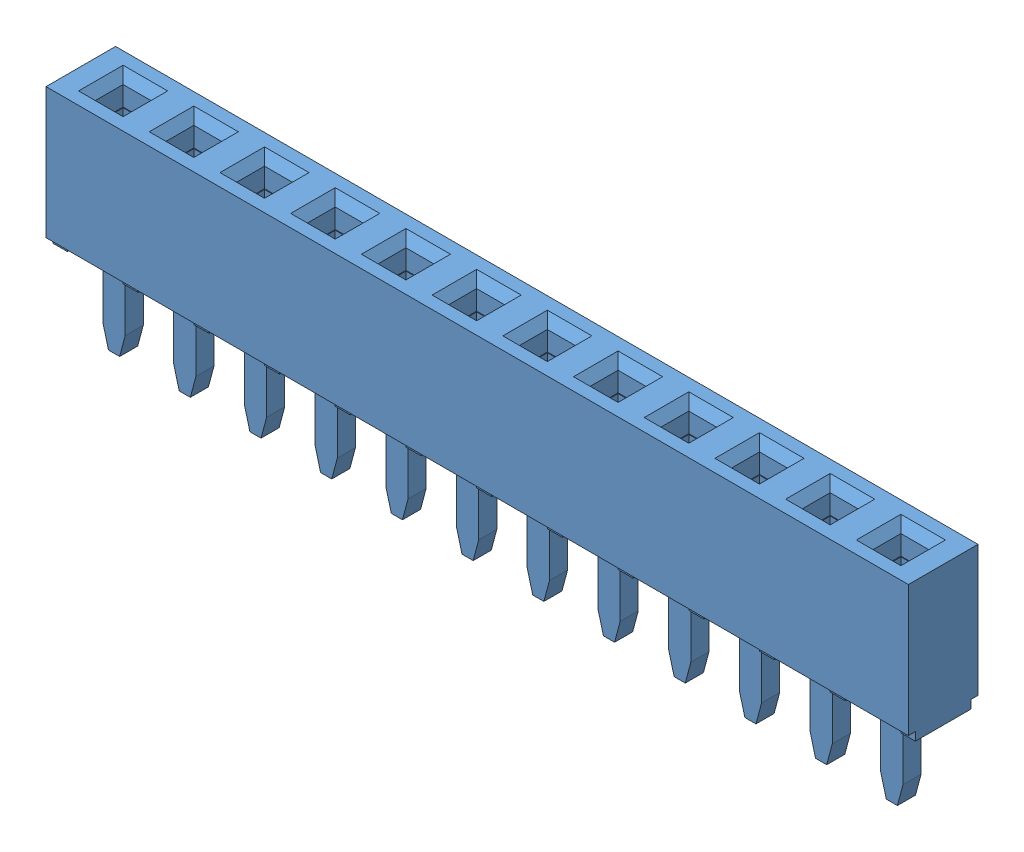
SolidWorks assembly pinheader-2.54mm-female-12, configuration Default. Lengths in mm.
Overall size (30.98 8 2.5).
2 component instances, 1 part files, 0 mates.
Components (placement in the parent):
- 12-Pin Header - Female - 2.54mm(2)^pinheader-2.54mm-female-12-1: 12-Pin Header - Female - 2.54mm(2)^pinheader-2.54mm-female-12 [Default] at origin size (30.98 8 2.5) (virtual)
  - 12er Pin Header Female^12-Pin Header - Female - 2.54mm(2)_pinheader-2.54mm-female-12-1: 12er Pin Header Female^12-Pin Header - Female - 2.54mm(2)_pinheader-2.54mm-female-12 [Default] at (24.13 0 0) size (30.98 8 2.5) (virtual)
